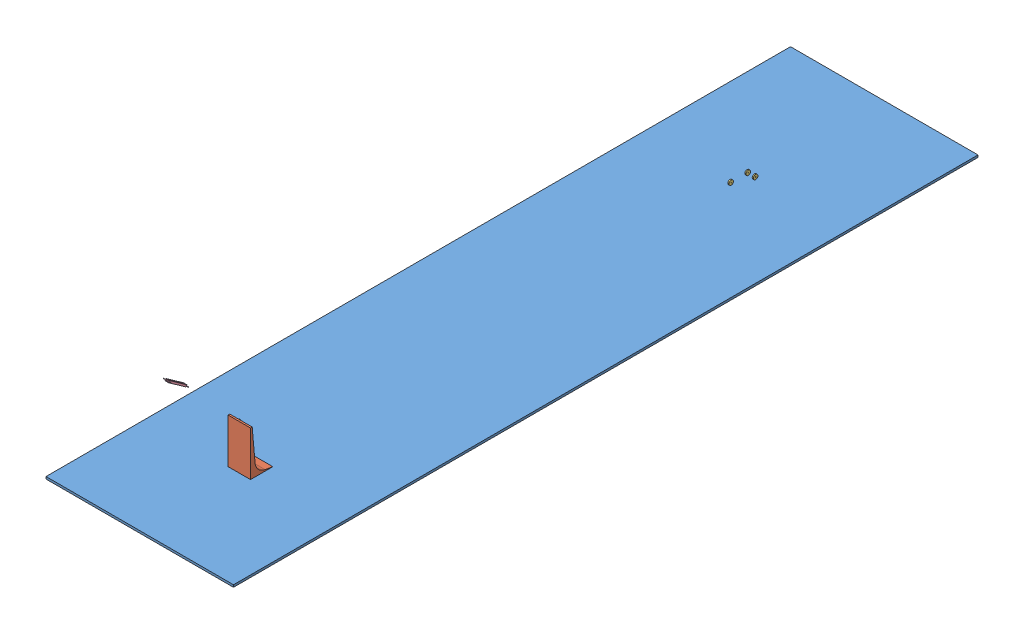
SolidWorks assembly motion analysis, configuration Default. Lengths in mm.
Overall size (13583.82 1050 16654.85).
7 component instances, 4 part files, 15 mates.
Components (placement in the parent):
- floor arc-1: floor arc [Default] at (5387.7735 19928.8872 6235.1989) size (13583.82 50 16654.85)
- Ramp-2: Ramp [Default] at (5637.7735 19928.8872 6735.1989) size (500 1000 500)
- Front Wheel-2: Front Wheel [Default] at (5271.2329 20806.8914 6635.4316) x (0 0.604782 -0.796391) z (-1 0 0) size (101.6 101.6 25.4)
- Front Wheel-5: Front Wheel [Default] at (5298.8843 19978.4289 -4344.7518) x (0 -0.723292 0.690542) z (-1 0 0) size (101.6 101.6 25.4)
- Front Wheel-6: Front Wheel [Default] at (5298.8843 19978.4284 -4725.7518) x (0 -0.751956 -0.659213) z (-1 0 0) size (101.6 101.6 25.4)
- Front Wheel-7: Front Wheel [Default] at (5463.9843 19978.4284 -4725.7518) x (0 0.327343 0.944906) z (-1 0 0) size (101.6 101.6 25.4)
- frame-1: frame [Default] at (3632.3767 20556.0519 6253.6657) x (0.189687 -0.529182 -0.827034) z (0.981367 0.128455 0.142892) size (395.3 38.1 196.34)
Mates (geometry in assembly coordinates):
- Coincident1: coincident: point of floor arc-1; moEndPointRef_w of Ramp-2
- Tangent1: tangent: plane of Ramp-2 through (5137.7735 20928.8872 6697.0989) normal (0 0.087156 -0.996195); cylinder of Front Wheel-2 through (5283.9329 20806.8914 6635.4316) axis (-1 0 0) radius 50.8
- Parallel3: parallel: plane of floor arc-1 through (7484.8335 19878.8872 8962.7211) normal (1 0 0); plane of Ramp-2 through (5637.7735 20228.3882 6361.8044) normal (1 0 0)
- Coincident6: coincident: plane of floor arc-1 through (5387.7735 19928.8872 6235.1989) normal (0 1 0); plane of Ramp-2 through (5137.7735 19928.8872 6735.1989) normal (0 -1 0)
- Parallel4: parallel: plane of Ramp-2 through (5637.7735 20228.3882 6361.8044) normal (1 0 0); plane of Front Wheel-2 through (5283.9329 20806.8914 6635.4316) normal (1 0 0)
- Tangent5: tangent: plane of Ramp-2; cylinder of Front Wheel-7 through (5391.228 19977.2179 -2701.9897) axis (-0.937563 -0.000817 -0.347813) radius 50.8
- Concentric4: concentric: cylinder of Front Wheel-2 through (5579.0357 20823.2773 6591.2543) axis (-0.928113 0 0.372299) radius 6.35; cylinder of frame-1 through (5579.0357 20823.2773 6591.2543) axis (-0.928113 0 0.372299) radius 5.08
- Coincident21: coincident: plane of Front Wheel-2; plane of frame-1
- Concentric5: concentric: cylinder of Front Wheel-5 through (5425.8043 20823.2773 6652.7208) axis (-0.928113 0 0.372299) radius 6.35; cylinder of frame-1 through (5579.0357 20823.2773 6591.2543) axis (-0.928113 0 0.372299) radius 5.08
- Coincident22: coincident: plane of Front Wheel-5; plane of frame-1
- Concentric8: concentric: cylinder of Front Wheel-7 through (5572.0069 20445.2913 6558.4429) axis (-0.928669 -0.029882 0.369705) radius 6.35; cylinder of frame-1 through (5572.0069 20445.2913 6558.4429) axis (-0.928669 -0.029882 0.369705) radius 5.08
- Coincident25: coincident: plane of Front Wheel-7; plane of frame-1
- Concentric9: concentric: cylinder of Front Wheel-6 through (5418.6837 20440.3577 6619.4811) axis (-0.928669 -0.029882 0.369705) radius 6.35; cylinder of frame-1 through (5572.0069 20445.2913 6558.4429) axis (-0.928669 -0.029882 0.369705) radius 5.08
- Coincident26: coincident: plane of Front Wheel-6; plane of frame-1
- Coincident30: coincident: line of floor arc-1 through (5346.0084 19928.8872 6251.9523) axis (0.928113 0 -0.372299); line of Ramp-2 through (5155.7453 19928.8872 6328.2736) axis (0.928113 0 -0.372299)
